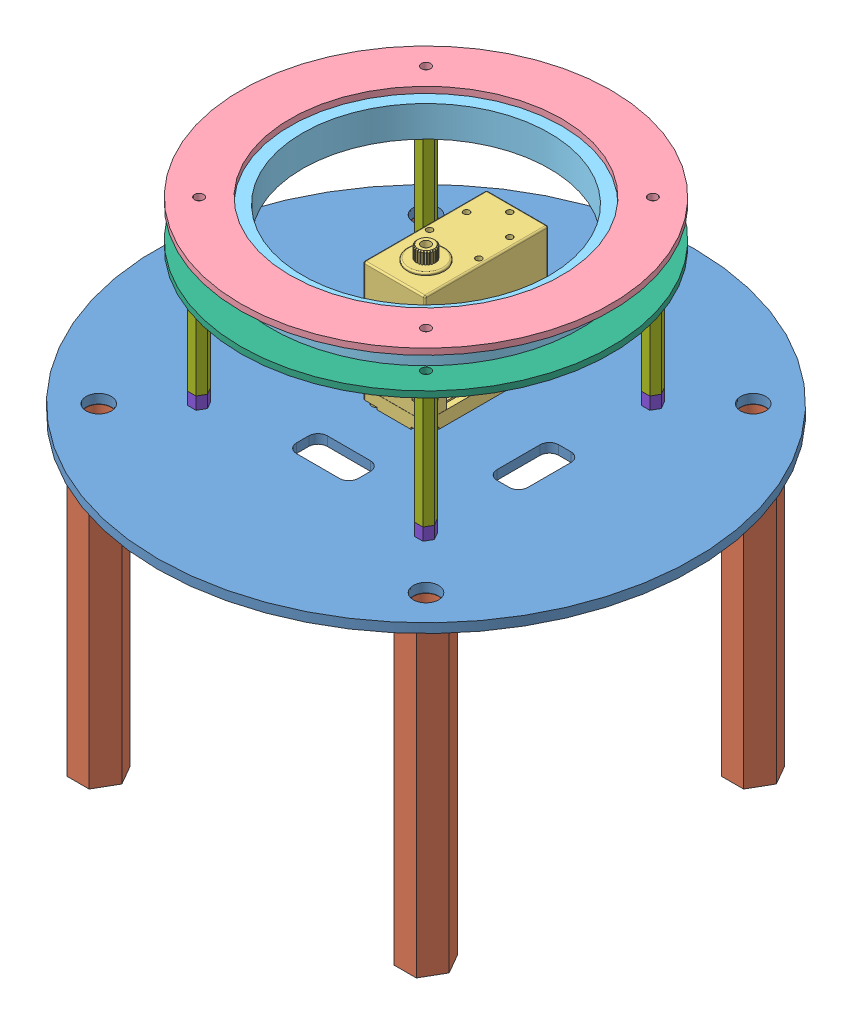
SolidWorks assembly base, configuration 默认. Lengths in mm.
Overall size (174 161 174).
18 component instances, 9 part files, 31 mates.
Components (placement in the parent):
- 1号舵机底座-1: 1号舵机底座 [默认] at (0 103 0) size (174 3 174)
- M8×100铜柱-1: M8×100铜柱 [默认] at (-53.9281 0 -53.9802) size (15.01 100 13)
- M8×100铜柱-2: M8×100铜柱 [默认] at (52.1379 0 52.0858) size (15.01 100 13)
- M8×100铜柱-3: M8×100铜柱 [默认] at (52.1379 0 -53.9802) size (15.01 100 13)
- M8×100铜柱-4: M8×100铜柱 [默认] at (-53.9281 0 52.0858) size (15.01 100 13)
- 云台外壳-1: 云台外壳 [默认] at (0 161 0) x (0.707107 0 0.707107) z (-0.707107 0 0.707107) size (180 164 180) (hidden)
- 舵机-2: 舵机 [默认] at (0 103.2 -9.65) x (0 0 1) z (-1 0 0) size (40 51.4 20)
- 轴承外顶-1: 轴承外顶 [默认] at (0 161 0) size (120 2 120)
- 轴承-1: 轴承 [默认] at (0 149 0) x (0.957428 0 0.288672) z (-0.288672 0 0.957428) size (100 10 100)
- 轴承外底座-1: 轴承外底座 [默认] at (0 149 0) size (120 2 120)
- M3×40铜柱-1: M3×40铜柱 [默认] at (-36.7696 107 -36.7696) size (5.43 40 4.7)
- M3×40铜柱-2: M3×40铜柱 [默认] at (36.7696 107 36.7696) size (5.43 40 4.7)
- M3×40铜柱-3: M3×40铜柱 [默认] at (36.7696 107 -36.7696) size (5.43 40 4.7)
- M3×40铜柱-4: M3×40铜柱 [默认] at (-36.7696 107 36.7696) size (5.43 40 4.7)
- M3×4铜柱-1: M3×4铜柱 [默认] at (-36.7696 103 36.7696) size (5.43 4 4.7)
- M3×4铜柱-2: M3×4铜柱 [默认] at (-36.7696 103 -36.7696) size (5.43 4 4.7)
- M3×4铜柱-3: M3×4铜柱 [默认] at (36.7696 103 36.7696) size (5.43 4 4.7)
- M3×4铜柱-4: M3×4铜柱 [默认] at (36.7696 103 -36.7696) size (5.43 4 4.7)
Mates (geometry in assembly coordinates):
- 同心2: concentric aligned: circle of 6号舵机底座-1; circle of M8×100铜柱-2
- 重合3: coincident anti-aligned: plane of 6号舵机底座-1 through (0 100 0) normal (0 -1 0); plane of M8×100铜柱-2 through (52.1379 100 52.0858) normal (0 1 0)
- 同心3: concentric aligned: circle of 6号舵机底座-1; circle of M8×100铜柱-4
- 重合4: coincident anti-aligned: plane of 6号舵机底座-1 through (0 100 0) normal (0 -1 0); plane of M8×100铜柱-4 through (-53.9281 100 52.0858) normal (0 1 0)
- 同心4: concentric aligned: circle of 6号舵机底座-1; circle of M8×100铜柱-1
- 重合5: coincident anti-aligned: plane of 6号舵机底座-1 through (0 100 0) normal (0 -1 0); plane of M8×100铜柱-1 through (-53.9281 100 -53.9802) normal (0 1 0)
- 同心5: concentric aligned: circle of 6号舵机底座-1; circle of M8×100铜柱-3
- 重合6: coincident anti-aligned: plane of 6号舵机底座-1 through (0 100 0) normal (0 -1 0); plane of M8×100铜柱-3 through (52.1379 100 -53.9802) normal (0 1 0)
- 重合8: coincident aligned: plane of M8×100铜柱-1 through (-53.9281 0 -53.9802) normal (0 -1 0)
- 重合12: coincident anti-aligned: plane of 6号舵机底座-1 through (0 103 0) normal (0 1 0); plane of 云台外壳-1 through (0 103 0) normal (0 -1 0)
- 重合13: coincident aligned: circle of 6号舵机底座-1; circle of 云台外壳-1
- 重合14: coincident aligned: circle of 6号舵机底座-1; circle of 云台外壳-1
- 距离1: distance = 0.2 mm anti-aligned: plane of 6号舵机底座-1 through (0 103 0) normal (0 1 0); plane of 舵机-2 through (0 103.2 -9.65) normal (0 -1 0)
- 同心6: concentric anti-aligned: circle of 6号舵机底座-1; circle of 舵机-2
- 同心13: concentric aligned: circle of 6号舵机底座-1; circle of 舵机-2
- 同心7: concentric aligned: circle of 云台外壳-1; circle of 轴承外顶-1
- 同心8: concentric aligned: circle of 云台外壳-1; circle of 轴承外顶-1
- 重合20: coincident anti-aligned: plane of 云台外壳-1 through (0 161 0) normal (0 -1 0); plane of 轴承外顶-1 through (0 161 0) normal (0 1 0)
- 同心9: concentric aligned: circle of 轴承外顶-1; circle of 轴承-1
- 重合21: coincident anti-aligned: plane of 轴承外顶-1 through (0 159 0) normal (0 -1 0); plane of 轴承-1 through (0 159 0) normal (0 1 0)
- 同心10: concentric aligned: circle of 轴承外顶-1; circle of 轴承外底座-1
- 同心11: concentric aligned: circle of 轴承外顶-1; circle of 轴承外底座-1
- 重合24: coincident anti-aligned: plane of 轴承-1 through (0 149 0) normal (0 -1 0); plane of 轴承外底座-1 through (0 149 0) normal (0 1 0)
- 重合25: coincident anti-aligned: circle of 轴承外底座-1; circle of M3×40铜柱-4
- 重合26: coincident anti-aligned: circle of 轴承外底座-1; circle of M3×40铜柱-2
- 重合27: coincident anti-aligned: circle of 轴承外底座-1; circle of M3×40铜柱-3
- 重合28: coincident anti-aligned: circle of 轴承外底座-1; circle of M3×40铜柱-1
- 重合29: coincident aligned: circle of 6号舵机底座-1; circle of M3×4铜柱-4
- 重合30: coincident aligned: circle of 6号舵机底座-1; circle of M3×4铜柱-3
- 重合31: coincident aligned: circle of 6号舵机底座-1; circle of M3×4铜柱-1
- 重合32: coincident aligned: circle of 6号舵机底座-1; circle of M3×4铜柱-2
